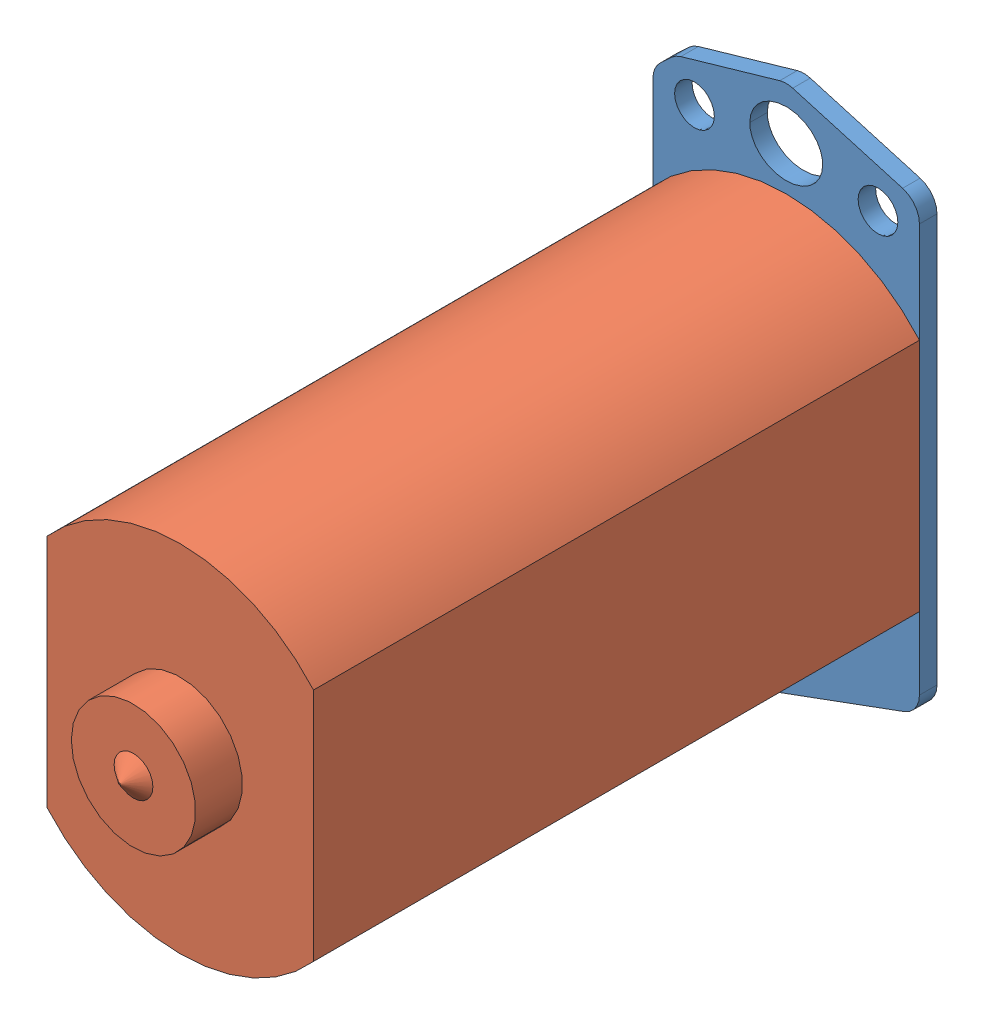
SolidWorks assembly Window Motor_Motor Assembly, configuration Default. Lengths in mm.
Overall size (28.96 59.84 74.35).
2 component instances, 2 part files, 3 mates.
Components (placement in the parent):
- Window Motor_Motor2-1: Window Motor_Motor2 [Default] at (46.4134 0 -0.4583) size (28.96 59.84 1.91)
- Window Motor_Motor1-1: Window Motor_Motor1 [Default] at (46.4134 0.0469 1.4467) size (28.96 38.61 72.44)
Mates (geometry in assembly coordinates):
- Coincident1: coincident aligned: plane of Window Motor_Motor2-1 through (60.8914 -0.127 -64.3901) normal (1 0 0); plane of Window Motor_Motor1-1 through (60.8914 -42.5633 -64.3901) normal (1 0 0)
- Coincident2: coincident anti-aligned: plane of Window Motor_Motor2-1 through (-5.5083 -0.127 -64.3901) normal (0 0 1); plane of Window Motor_Motor1-1 through (46.4134 -42.5633 -64.3901) normal (0 0 -1)
- Distance1: distance = 10.16 mm: point of Window Motor_Motor2-1; point of Window Motor_Motor1-1
